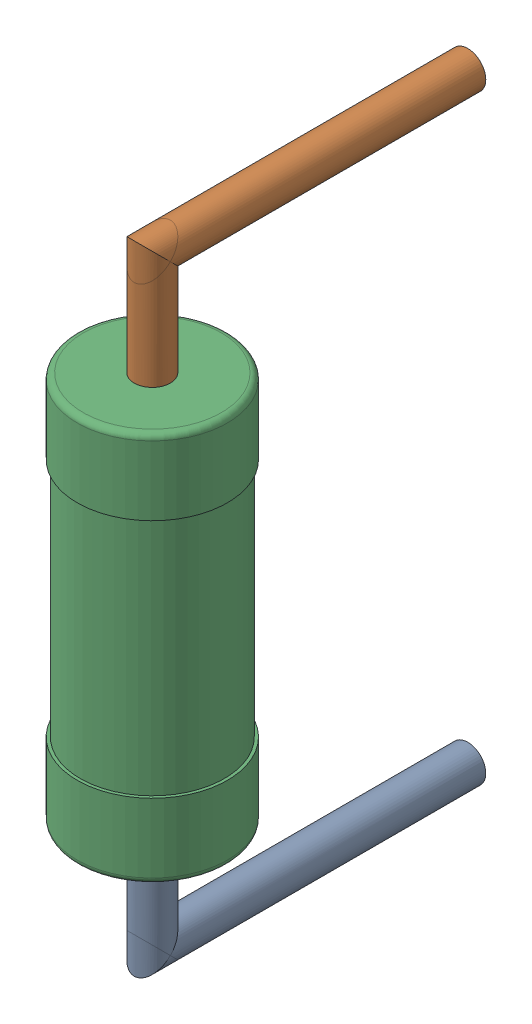
SolidWorks assembly R1.step, configuration Default. Lengths in mm.
Overall size (2.5 10.6 6.5).
3 component instances, 3 part files, 0 mates.
Components (placement in the parent):
- Res_Vishay_BC_Components_MRS25000C1101FCT00_eec.step-1: Res_Vishay_BC_Components_MRS25000C1101FCT00_eec.step [Default] at (15.748 43.307 0) x (0 1 0) z (0 0 1) size (2.05 0.6 5.55)
- Res_Vishay_BC_Components_MRS25000C1101FCT00_eec-2.step-1: Res_Vishay_BC_Components_MRS25000C1101FCT00_eec-2.step [Default] at (15.748 43.307 0) x (0 1 0) z (0 0 1) size (2.05 0.6 5.55)
- Res_Vishay_BC_Components_MRS25000C1101FCT00_eec-3.step-1: Res_Vishay_BC_Components_MRS25000C1101FCT00_eec-3.step [Default] at (15.748 43.307 0) x (0 1 0) z (0 0 1) size (6.5 2.5 2.5)
